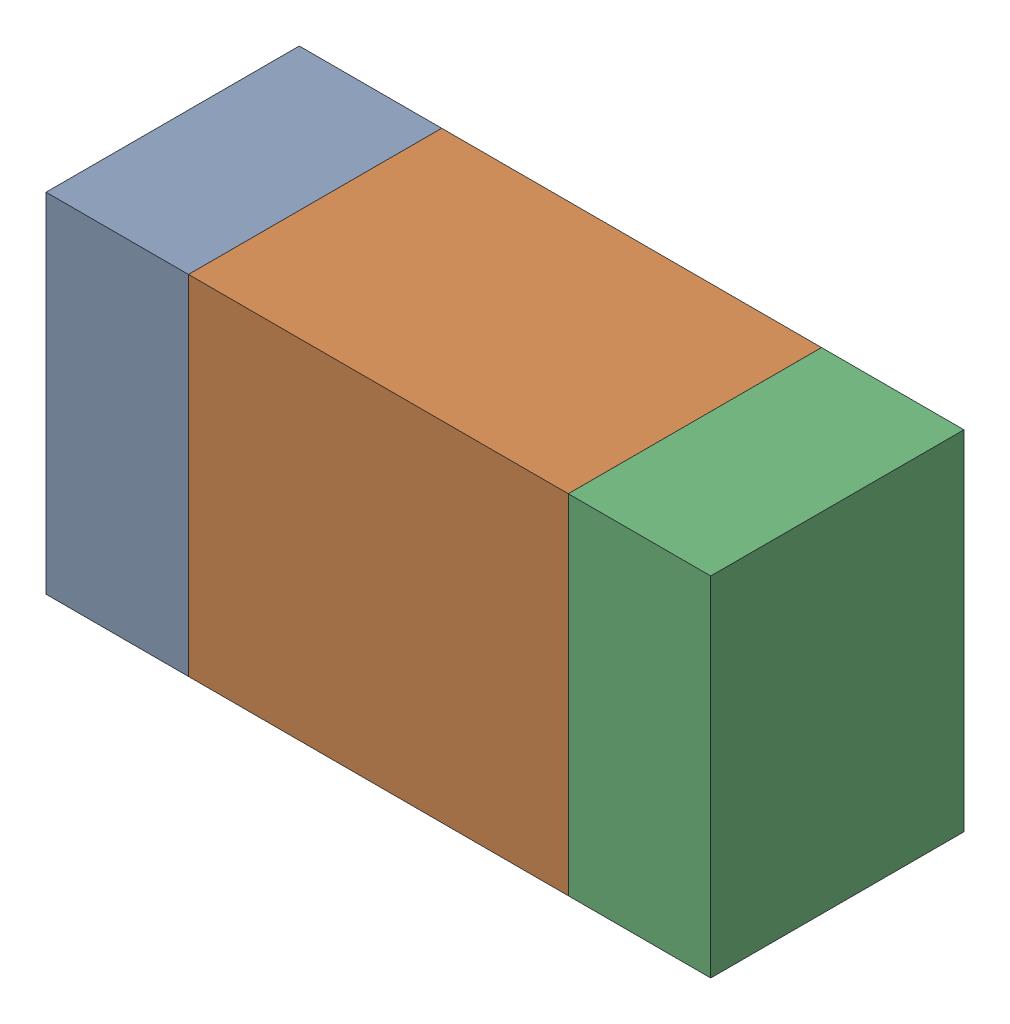
SolidWorks assembly R306_2PCB, configuration Default. Lengths in mm.
Overall size (1.05 0.55 0.4).
6 component instances, 2 part files, 0 mates.
Components (placement in the parent):
- 854785432-1: 854785432 [Default] at (140.6874 85.7999 0) size (0.22 0.55 0.4)
  - Extruded-1: Extruded [Default] at origin size (0.22 0.55 0.4)
- 854785568-1: 854785568 [Default] at (141.0999 85.7999 0) size (0.6 0.55 0.4)
  - Extruded_2-1: Extruded_2 [Default] at origin size (0.6 0.55 0.4)
- 854785432-2: 854785432 [Default] at (141.5124 85.7999 0) size (0.22 0.55 0.4)
  - Extruded-1: Extruded [Default] at origin size (0.22 0.55 0.4)
